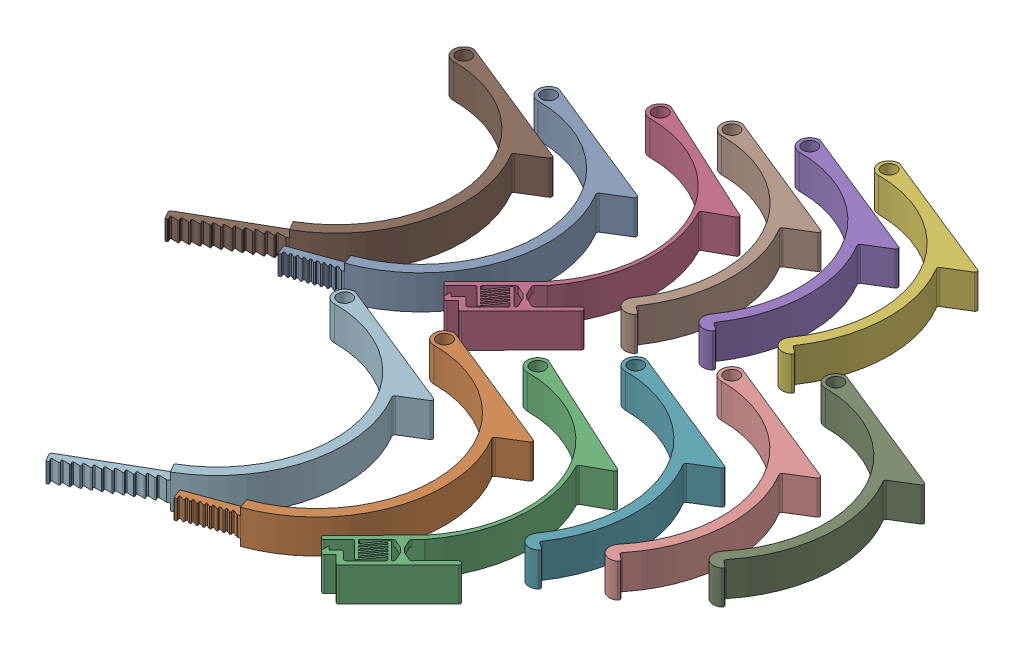
SolidWorks assembly ArmBandforPrinting v2, configuration Default. Lengths in mm.
Overall size (238.51 13 259.96).
12 component instances, 5 part files, 11 mates.
Components (placement in the parent):
- Arm Clamp inner v3-1: Arm Clamp inner v3 [Default] at (-32.6431 -2.162 1.9873) size (54.95 13 105.8)
- Arm Clamp inner v3-2: Arm Clamp inner v3 [Default] at (28.5436 -2.162 103.15) size (54.95 13 105.8)
- Arm Clamp v3-1: Arm Clamp v3 [Default] at (55.4382 -2.162 94.21) size (55.12 13 108.47)
- Arm Clamp v3-2: Arm Clamp v3 [Default] at (-5.4704 -2.162 -13.6811) size (55.12 13 108.47)
- Arm Clamp v5-1: Arm Clamp v5 [Default] at (34.5121 -2.162 -31.134) size (54.95 13 85.1)
- Arm Clamp v5-2: Arm Clamp v5 [Default] at (57.4158 -2.162 -38.6397) size (54.95 13 85.1)
- Arm Clamp v5-3: Arm Clamp v5 [Default] at (73.9173 -2.162 75.0685) size (54.95 13 85.1)
- Arm Clamp v5-4: Arm Clamp v5 [Default] at (14.0879 -2.162 -21.697) size (54.95 13 85.1)
- Arm Clamp v4-5: Arm Clamp v4 [Default] at (117.942 -2.162 42.3319) size (54.95 13 88.49)
- Arm Clamp v4-6: Arm Clamp v4 [Default] at (95.6742 -2.162 59.9809) size (54.95 13 88.49)
- Arm Clamp inner v3.1-1: Arm Clamp inner v3.1 [Default] at (-62.0979 -2.162 5.0752) size (58.47 13 112.82)
- Arm Clamp inner v3.1-2: Arm Clamp inner v3.1 [Default] at (-4.3993 -2.162 108.4964) size (58.47 13 112.82)
Mates (geometry in assembly coordinates):
- Coincident1: coincident aligned: plane of Arm Clamp inner v3-1 through (-32.6431 -2.162 1.9873) normal (0 -1 0); plane of Arm Clamp v3-1 through (55.4382 -2.162 94.21) normal (0 -1 0)
- Coincident2: coincident aligned: plane of Arm Clamp inner v3-1 through (-32.6431 -2.162 1.9873) normal (0 -1 0); plane of Arm Clamp v3-2 through (-5.4704 -2.162 -13.6811) normal (0 -1 0)
- Coincident3: coincident aligned: plane of Arm Clamp inner v3-1 through (-32.6431 -2.162 1.9873) normal (0 -1 0); plane of Arm Clamp inner v3-2 through (28.5436 -2.162 103.15) normal (0 -1 0)
- Coincident4: coincident aligned: plane of Arm Clamp inner v3-1 through (-32.6431 -2.162 1.9873) normal (0 -1 0); plane of Arm Clamp v4-5 through (117.942 -2.162 42.3319) normal (0 -1 0)
- Coincident5: coincident aligned: plane of Arm Clamp inner v3-1 through (-32.6431 -2.162 1.9873) normal (0 -1 0); plane of Arm Clamp v4-6 through (95.6742 -2.162 59.9809) normal (0 -1 0)
- Coincident6: coincident aligned: plane of Arm Clamp inner v3-1 through (-32.6431 -2.162 1.9873) normal (0 -1 0); plane of Arm Clamp v5-1 through (34.5121 -2.162 -31.134) normal (0 -1 0)
- Coincident7: coincident aligned: plane of Arm Clamp inner v3-1 through (-32.6431 -2.162 1.9873) normal (0 -1 0); plane of Arm Clamp v5-2 through (57.4158 -2.162 -38.6397) normal (0 -1 0)
- Coincident9: coincident aligned: plane of Arm Clamp inner v3-1 through (-32.6431 -2.162 1.9873) normal (0 -1 0); plane of Arm Clamp v5-3 through (73.9173 -2.162 75.0685) normal (0 -1 0)
- Coincident10: coincident aligned: plane of Arm Clamp inner v3-1 through (-32.6431 -2.162 1.9873) normal (0 -1 0); plane of Arm Clamp v5-4 through (14.0879 -2.162 -21.697) normal (0 -1 0)
- Coincident11: coincident aligned: plane of Arm Clamp inner v3-1 through (-32.6431 -2.162 1.9873) normal (0 -1 0); plane of Arm Clamp inner v3.1-1 through (-62.0979 -2.162 5.0752) normal (0 -1 0)
- Coincident12: coincident aligned: plane of Arm Clamp inner v3-1 through (-32.6431 -2.162 1.9873) normal (0 -1 0); plane of Arm Clamp inner v3.1-2 through (-4.3993 -2.162 108.4964) normal (0 -1 0)
